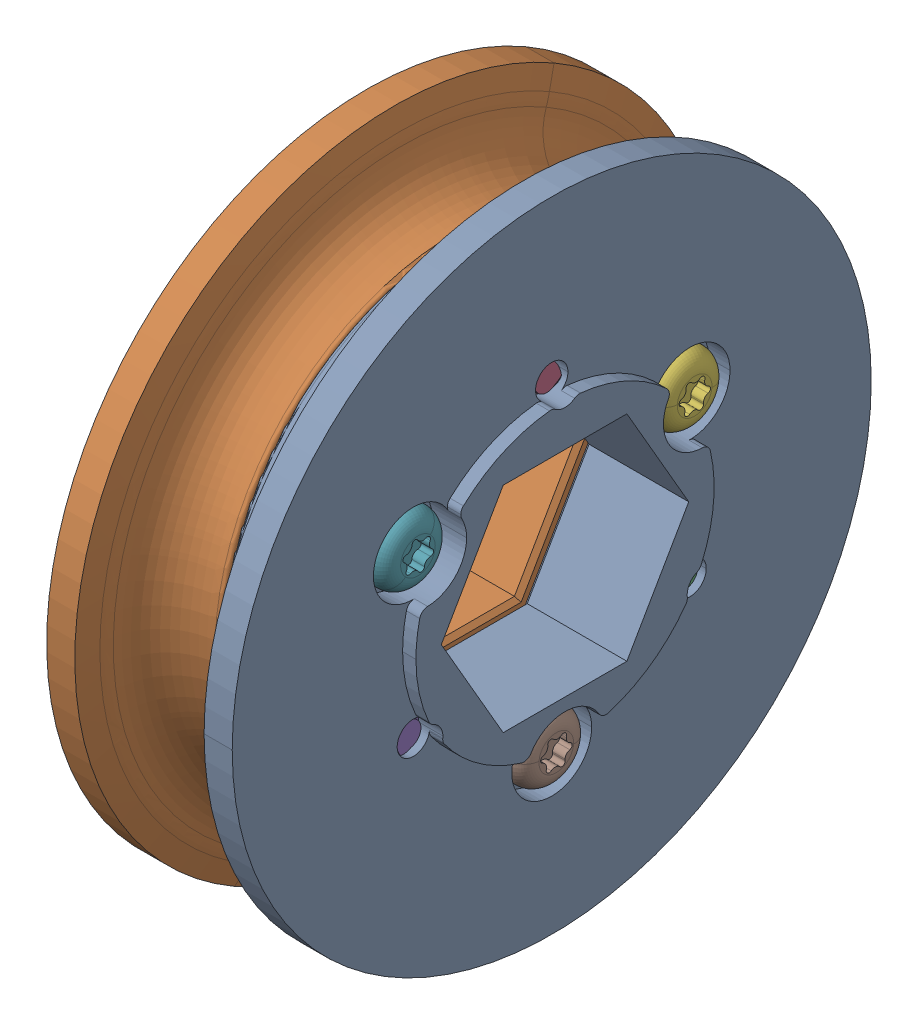
SolidWorks assembly WCP-0096 Rev6.step, configuration Default. Lengths in mm.
Overall size (12.65 52.05 52.05).
8 component instances, 2 part files, 0 mates.
Components (placement in the parent):
- WCP-0096-001 Rev6.step-1: WCP-0096-001 Rev6.step [Default] at origin size (7.57 38.1 38.1)
- WCP-0096-001 Rev6.step-2: WCP-0096-001 Rev6.step [Default] x (-1 0 0) z (0 0.866025 -0.5) size (7.57 38.1 38.1)
- WCP-0356 Rev1.step-1: WCP-0356 Rev1.step [Default] at (0.4817 -4.7625 -8.2489) x (0 -0.126969 0.991907) z (0 -0.991907 -0.126969) size (4.06 11.05 4.06)
- WCP-0356 Rev1.step-2: WCP-0356 Rev1.step [Default] at (0.4817 9.525 0) x (0 0.866766 0.498715) z (0 -0.498715 0.866766) size (4.06 11.05 4.06)
- WCP-0356 Rev1.step-3: WCP-0356 Rev1.step [Default] at (0.4817 -4.7625 8.2489) x (0 -0.994015 -0.109248) z (0 0.109248 -0.994015) size (4.06 11.05 4.06)
- WCP-0356 Rev1.step-4: WCP-0356 Rev1.step [Default] at (-0.4817 4.7625 -8.2489) x (0 -0.997555 0.069879) z (0 0.069879 0.997555) size (4.06 11.05 4.06)
- WCP-0356 Rev1.step-5: WCP-0356 Rev1.step [Default] at (-0.4817 4.7625 8.2489) x (0 -0.7202 -0.693767) z (0 -0.693767 0.7202) size (4.06 11.05 4.06)
- WCP-0356 Rev1.step-6: WCP-0356 Rev1.step [Default] at (-0.4817 -9.525 0) x (0 -0.997555 0.069879) z (0 0.069879 0.997555) size (4.06 11.05 4.06)
